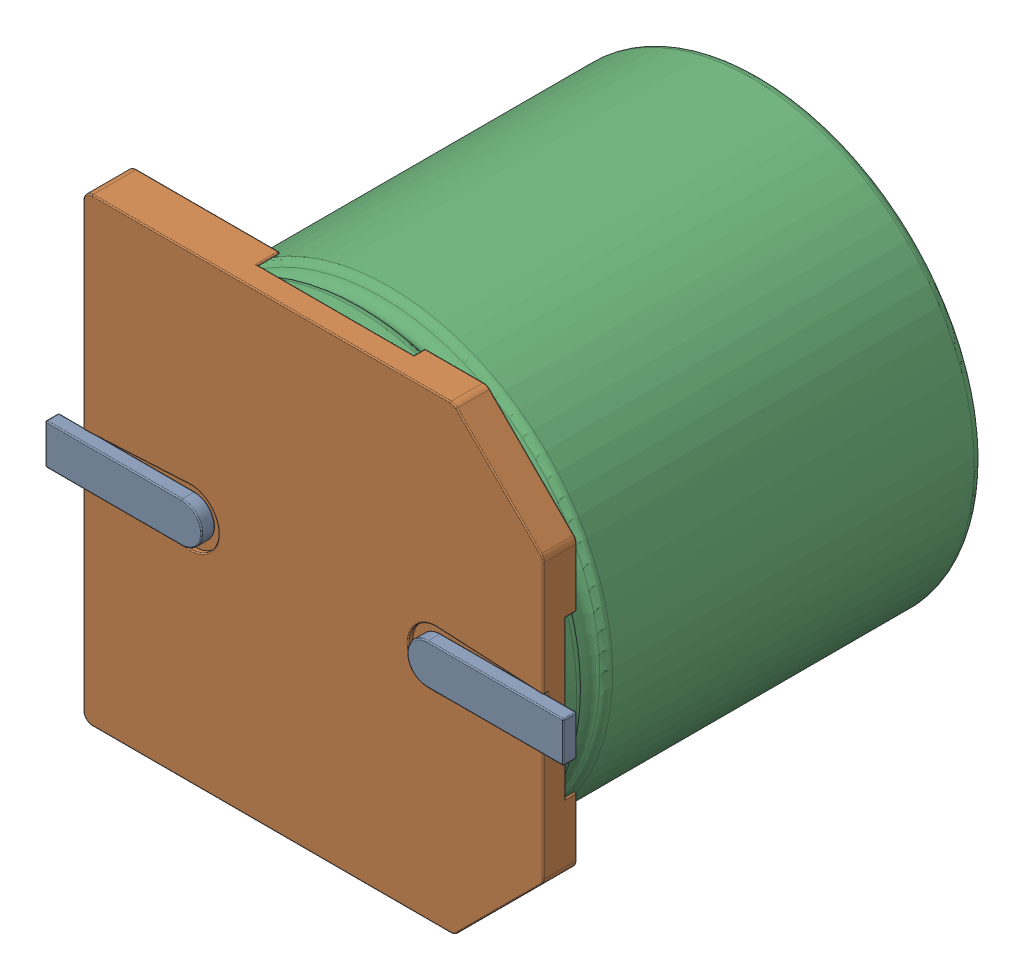
SolidWorks assembly C29, configuration Default. Lengths in mm.
Overall size (11.6 10.3 10.2).
5 component instances, 4 part files, 0 mates.
Components (placement in the parent):
- User_Library-ALU-G-1: User_Library-ALU-G [Default] at (26.6701 17.1449 -1.6914) x (1 0 0) z (0 0 -1) size (11.6 10.3 10.2)
  - Pins_1-1: Pins_1 [Default] at origin size (11.6 0.9 0.35)
  - Fuss_1-1: Fuss_1 [Default] at origin size (10.3 10.3 1)
  - K_X_F6rper_1-1: K_X_F6rper_1 [Default] at origin size (10 10 9.5)
  - Beschriftung_1-1: Beschriftung_1 [Default] at origin size (7.49 8.07 0.06)
